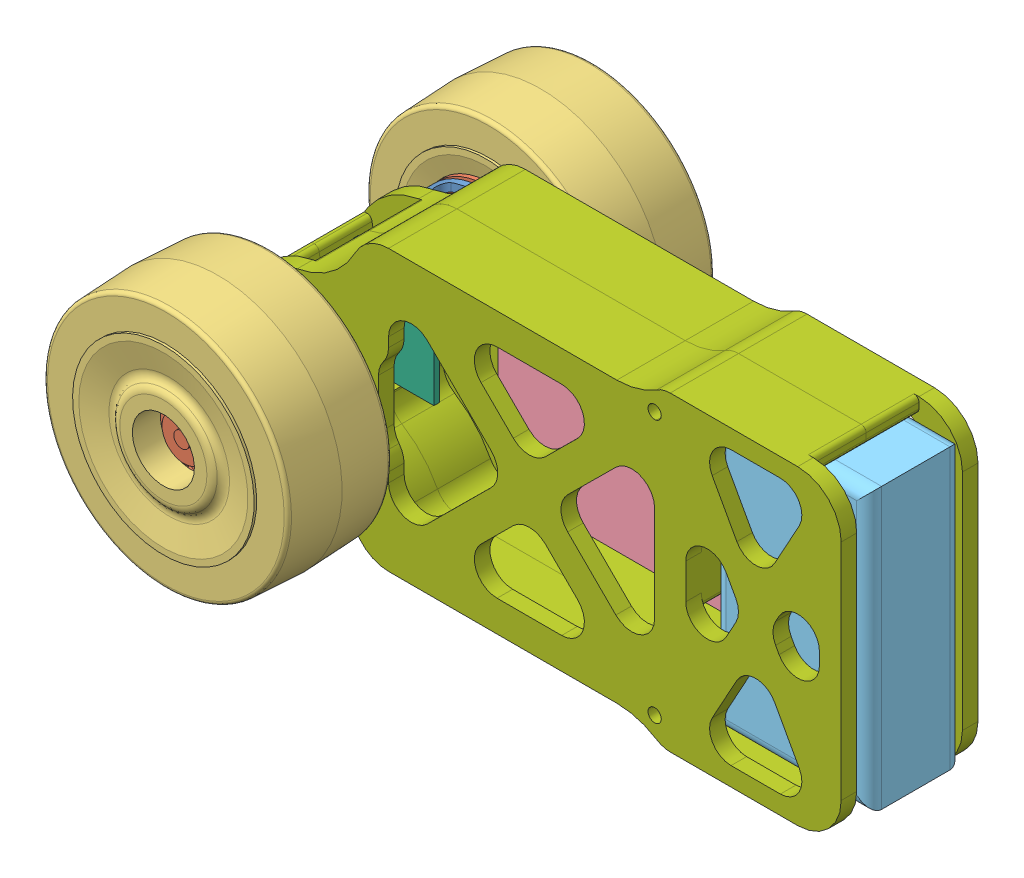
SolidWorks assembly bal_bot_assembly, configuration Default. Lengths in mm.
Overall size (142.14 67.62 88.17).
11 component instances, 7 part files, 24 mates.
Components (placement in the parent):
- motor bottom-1: motor bottom [Default] at origin size (27.64 27.64 21.52)
- motor bottom-2: motor bottom [Default] at (0 0 42.14) x (-0.708696 -0.705514 0) z (0 0 -1) size (27.64 27.64 21.52)
- motor top-1: motor top [Default] at (0 0 42.94) x (-0.084419 -0.99643 0) z (-0.99643 0.084419 0) size (27.64 26.5 27.64)
- motor top-2: motor top [Default] at (0 0 -0.8) x (-0.923728 -0.383049 0) z (0.383049 -0.923728 0) size (27.64 26.5 27.64)
- wheel-1: wheel [Default] at (0 0 -11.9025) x (0.980807 -0.194982 0) z (-0.194982 -0.980807 0) size (50.8 22.23 50.8)
- wheel-2: wheel [Default] at (0 0 54.0425) x (-0.426671 -0.904407 0) z (0.904407 -0.426671 0) size (50.8 22.23 50.8)
- main-1: main [Default] at (39.882 -0.019 10.275) size (50.37 50.37 1.27)
- battery-1: battery [Default] at (76.581 -28.575 29.325) x (0 1 0) z (-1 0 0) size (57.15 19.05 31.75)
- acc-1: acc [Default] at (-7.4073 10.668 17.895) x (0 -1 0) z (0 0 1) size (21.34 16.51 2.7)
- body-1: body [Default] at (0 0 7.1) x (0 -1 0) z (0 0 1) size (63.5 124.21 13.97)
- body-2: body [Default] at (0 0 35.04) x (0 1 0) z (0 0 -1) size (63.5 124.21 13.97)
Mates (geometry in assembly coordinates):
- Concentric1: concentric anti-aligned: cylinder of motor bottom-1 through (0 0 7.1) axis (0 0 -1) radius 13.8176; cylinder of motor bottom-2 through (0 0 35.04) axis (0 0 1) radius 13.8176
- Concentric2: concentric aligned: cylinder of motor bottom-1 through (0 0 -14.424) axis (0 0 1) radius 3.81; cylinder of motor top-2 through (0 0 -19.3) axis (0 0 1) radius 1.5875
- Concentric3: concentric aligned: cylinder of motor bottom-2 through (0 0 56.564) axis (0 0 -1) radius 3.81; cylinder of motor top-1 through (0 0 61.44) axis (0 0 -1) radius 1.5875
- Distance1: distance = 0.8 mm anti-aligned: plane of motor top-1 through (0 0 42.94) normal (0 0 -1); plane of motor bottom-2 through (0 0 42.14) normal (0 0 1)
- Distance2: distance = 0.8 mm anti-aligned: plane of motor top-2 through (0 0 -0.8) normal (0 0 1); plane of motor bottom-1 through (0 0 0) normal (0 0 -1)
- Concentric4: concentric anti-aligned: cylinder of motor top-1 through (0 0 59.44) axis (0 0 -1) radius 13.8176; cylinder of wheel-1 through (0 0 -17.3) axis (0 0 1) radius 13.9002
- Concentric5: concentric anti-aligned: cylinder of motor top-2 through (0 0 -17.3) axis (0 0 1) radius 13.8176; cylinder of wheel-2 through (0 0 59.44) axis (0 0 -1) radius 13.9002
- Coincident5: coincident anti-aligned: plane of motor top-1 through (0 0 59.44) normal (0 0 1); plane of wheel-2 through (0 0 59.44) normal (0 0 -1)
- Coincident6: coincident anti-aligned: plane of motor top-2 through (0 0 -17.3) normal (0 0 -1); plane of wheel-1 through (0 0 -17.3) normal (0 0 1)
- Concentric6: concentric aligned: cylinder of motor bottom-1 through (0 0 7.1) axis (0 0 -1) radius 13.8176; cylinder of body-1 through (0 0 10.275) axis (0 0 -1) radius 15.875
- Coincident7: coincident anti-aligned: plane of motor bottom-1 through (0 0 7.1) normal (0 0 1); plane of body-1 through (15.875 20.955 7.1) normal (0 0 -1)
- Concentric7: concentric anti-aligned: cylinder of motor bottom-1 through (-5.6569 -5.6569 7.1) axis (0 0 1) radius 1.25; cone of body-1 through (-5.6569 -5.6569 10.275) axis (0 0 -1)
- Parallel1: parallel aligned: plane of acc-1 through (-7.4073 10.668 20.595) normal (0 1 0); plane of body-1 through (15.875 28.575 10.275) normal (0 1 0)
- Coincident10: coincident anti-aligned: plane of main-1 through (65.0661 25.1651 10.275) normal (0 0 -1); plane of body-1 through (15.875 20.955 10.275) normal (0 0 1)
- Parallel2: parallel aligned: plane of main-1 through (14.6979 25.1651 11.545) normal (0 1 0); plane of body-1 through (15.875 28.575 10.275) normal (0 1 0)
- Coincident12: coincident anti-aligned: plane of battery-1 through (108.331 -28.575 10.275) normal (0 0 -1); plane of body-1 through (15.875 20.955 10.275) normal (0 0 1)
- Distance5: distance = 3.175 mm aligned: plane of battery-1 through (76.581 28.575 10.275) normal (0 1 0); plane of body-1 through (73.406 31.75 10.275) normal (0 1 0)
- Coincident15: coincident anti-aligned: plane of acc-1 through (9.1027 10.668 17.895) normal (0 0 -1); plane of body-1 through (15.875 20.955 17.895) normal (0 0 1)
- Coincident16: coincident anti-aligned: plane of acc-1 through (-7.4073 10.668 20.595) normal (0 1 0); plane of body-1 through (2.318 10.668 -11.6574) normal (0 -1 0)
- Coincident17: coincident anti-aligned: plane of motor bottom-2 through (0 0 35.04) normal (0 0 -1); plane of body-2 through (15.875 -20.955 35.04) normal (0 0 1)
- Concentric8: concentric aligned: cylinder of motor bottom-2 through (0 0 35.04) axis (0 0 1) radius 13.8176; cylinder of body-2 through (0 0 31.865) axis (0 0 1) radius 15.875
- Coincident18: coincident aligned: plane of body-1 through (15.875 28.575 10.275) normal (0 1 0); plane of body-2 through (62.4995 28.575 31.865) normal (0 1 0)
- Coincident20: coincident anti-aligned: plane of battery-1 through (76.581 -28.575 10.275) normal (-1 0 0); plane of body-2 through (76.581 -3.5991 31.865) normal (1 0 0)
- Coincident22: coincident anti-aligned: plane of body-1 through (-5.6345 -31.8911 21.07) normal (0 0 1); plane of body-2 through (15.875 -20.955 21.07) normal (0 0 -1)
